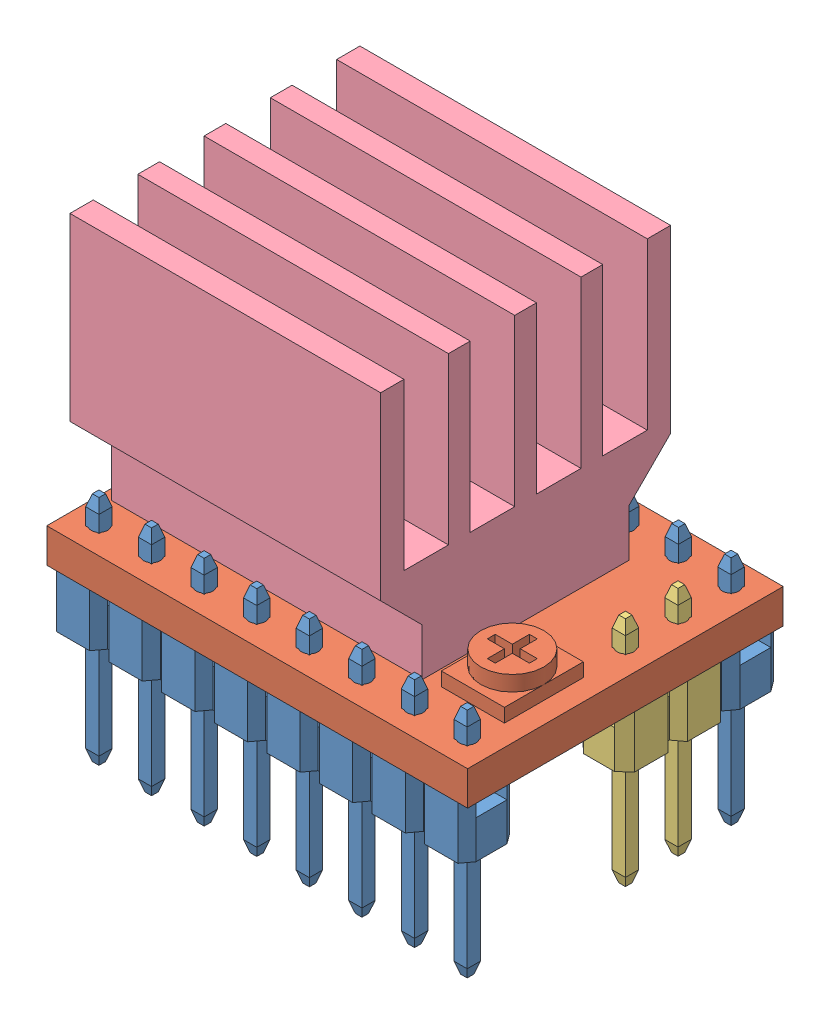
SolidWorks assembly Panucatt SD5984, configuration Default. Lengths in mm.
Overall size (20.32 22.85 15.24).
5 component instances, 4 part files, 15 mates.
Components (placement in the parent):
- pin_header_aw140-eg-g08d-1: pin_header_aw140-eg-g08d [Default] at (0 0 6.37) size (20.22 11.2 2.5)
- pin_header_aw140-eg-g08d-2: pin_header_aw140-eg-g08d [Default] at (0 0 -6.37) size (20.22 11.2 2.5)
- SD5984_PCB-1: SD5984_PCB [Default] at origin size (20.32 3.05 15.24)
- pin_header_aw140-eg-g02d-1: pin_header_aw140-eg-g02d [Default] at (8.89 0 -10.16) x (0 0 -1) z (1 0 0) size (5.08 11.2 2.5)
- Panucatt Heatsink-1: Panucatt Heatsink [Default] at (-9.66 1.651 0) x (0 0 -1) z (1 0 0) size (14 13 15)
Mates (geometry in assembly coordinates):
- Coincident42: coincident aligned: plane of SD5984_PCB-1 through (-10.16 1.651 7.62) normal (0 0 1); plane of pin_header_aw140-eg-g08d-1 through (-9.69 -2.54 7.62) normal (0 0 1)
- Coincident43: coincident aligned: plane of SD5984_PCB-1 through (-10.16 1.651 7.62) normal (-1 0 0); plane of pin_header_aw140-eg-g08d-1 through (-10.16 -2.54 7.12) normal (-1 0 0)
- Coincident44: coincident anti-aligned: plane of SD5984_PCB-1 through (0 0 0) normal (0 -1 0); plane of pin_header_aw140-eg-g08d-1 through (-7.72 0 7.62) normal (0 1 0)
- Coincident45: coincident aligned: plane of SD5984_PCB-1 through (-10.16 1.651 -7.62) normal (0 0 -1); plane of pin_header_aw140-eg-g08d-2 through (9.69 -2.54 -7.62) normal (0 0 -1)
- Coincident46: coincident aligned: plane of SD5984_PCB-1 through (-10.16 1.651 7.62) normal (-1 0 0); plane of pin_header_aw140-eg-g08d-2 through (-10.16 -2.54 -5.62) normal (-1 0 0)
- Coincident47: coincident anti-aligned: plane of SD5984_PCB-1 through (0 0 0) normal (0 -1 0); plane of pin_header_aw140-eg-g08d-2 through (-7.72 0 -5.12) normal (0 1 0)
- Coincident48: coincident aligned: plane of SD5984_PCB-1 through (0 0 0) normal (0 0 1); plane of assembly through (0 0 0) normal (0 0 1)
- Coincident49: coincident aligned: plane of SD5984_PCB-1 through (0 0 0) normal (0 1 0); plane of assembly through (0 0 0) normal (0 1 0)
- Coincident50: coincident aligned: plane of SD5984_PCB-1 through (0 0 0) normal (1 0 0); plane of assembly through (0 0 0) normal (1 0 0)
- Coincident51: coincident anti-aligned: plane of SD5984_PCB-1 through (0 0 0) normal (0 -1 0); plane of pin_header_aw140-eg-g02d-1 through (10.14 0 -2.44) normal (0 1 0)
- Concentric2: concentric aligned: cylinder of SD5984_PCB-1 through (8.89 -0.001 -1.27) axis (0 1 0) radius 0.3937; circle of pin_header_aw140-eg-g02d-1
- Concentric3: concentric aligned: cylinder of SD5984_PCB-1 through (8.89 -0.001 -3.81) axis (0 1 0) radius 0.3937; circle of pin_header_aw140-eg-g02d-1
- Coincident52: coincident anti-aligned: plane of Panucatt Heatsink-1 through (-9.66 1.651 0) normal (0 0 -1); plane of assembly through (0 0 0) normal (0 0 1)
- Coincident53: coincident anti-aligned: plane of SD5984_PCB-1 through (0 1.651 0) normal (0 1 0); plane of Panucatt Heatsink-1 through (5.34 1.651 0) normal (0 -1 0)
- Distance1: distance = 0.5 mm aligned: plane of Panucatt Heatsink-1 through (-9.66 1.651 0) normal (-1 0 0); plane of SD5984_PCB-1 through (-10.16 1.651 7.62) normal (-1 0 0)
